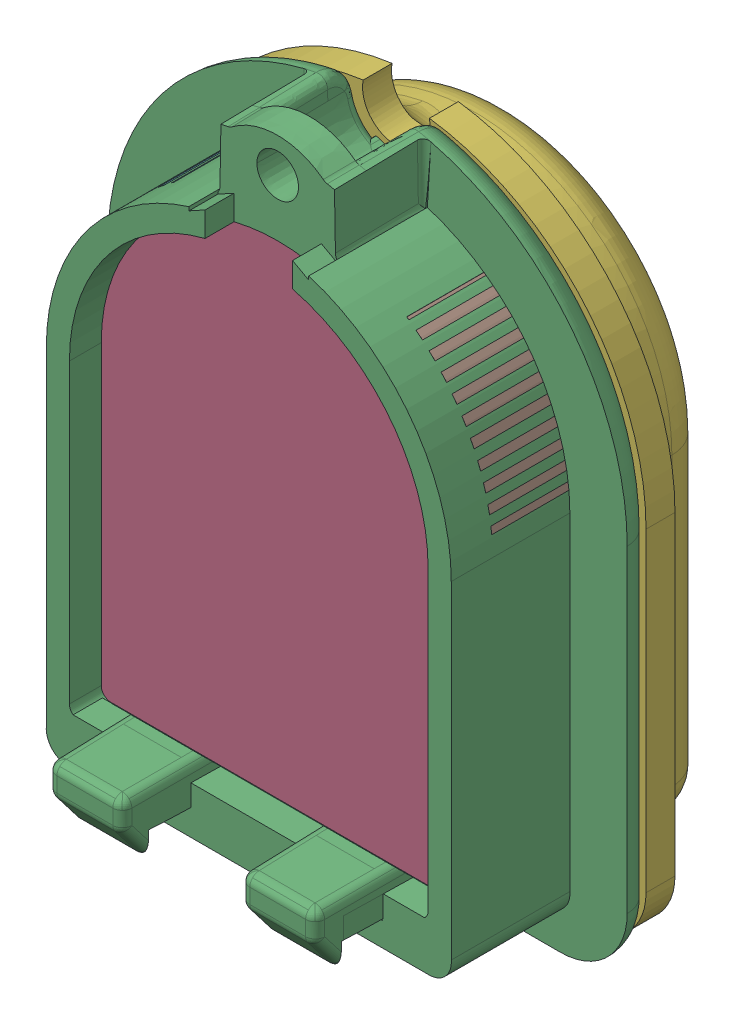
SolidWorks assembly newDesign, configuration 默认. Lengths in mm.
Overall size (26.95 34.26 17.16).
8 component instances, 7 part files, 21 mates.
Components (placement in the parent):
- NewBoardTip1-1: NewBoardTip1 [默认] at (-1.9035 7.7463 -5.5591) size (26.95 34.26 11.18)
- NewBoardlensnew-1: NewBoardlensnew [默认] at (-1.9035 7.7463 -5.5591) size (18.6 25.2 6)
- NewBoardSkin0.2-1: NewBoardSkin0.2 [默认] at (-1.9035 7.4963 -5.5591) x (-1 0 0) z (0 0 -1) size (23.9 30.06 5.2)
- NewSkin1-2: NewSkin1 [默认] at (-1.9035 7.4963 -5.5591) x (-1 0 0) z (0 0 -1) size (25.9 32.24 6)
- NewBoardsidelens1-1: NewBoardsidelens1 [默认] at (-1.9035 7.7463 -6.2091) size (6.4 7.71 4)
- NewBoardsidelens1-2: NewBoardsidelens1 [默认] at (-1.9035 7.7463 2.0909) x (-1 0 0) z (0 0 -1) size (6.4 7.71 4)
- NewBoardbottomlens-1: NewBoardbottomlens [默认] at (-5.9035 -10.5037 0.4409) x (1 0 0) z (0 1 0) size (8 4.5 2.35)
- NewBoardChessboardDigit-1: NewBoardChessboardDigit [默认] at (-15.1693 -0.6894 -10.3591) x (0 1 0) z (0 0 -1) size (22.5 14.3 0.4)
Mates (geometry in assembly coordinates):
- 同心1: concentric aligned: cylinder of BoardTip1-1 through (-1.9035 7.7463 51.2878) axis (0 0 -1) radius 9.3; cylinder of lensnew-1 through (-1.9035 7.7463 0.4409) axis (0 0 -1) radius 9.3
- 重合1: coincident anti-aligned: plane of BoardTip1-1 through (-1.9035 -8.1537 51.2878) normal (0 1 0); plane of lensnew-1 through (-11.2035 -8.1537 0.4409) normal (0 -1 0)
- 重合2: coincident aligned: plane of BoardTip1-1 through (-1.964 4.3089 -5.5591) normal (0 0 -1); plane of lensnew-1 through (-1.9035 7.7463 -5.5591) normal (0 0 -1)
- 重合3: coincident anti-aligned: plane of lensnew-1 through (-1.9035 7.7463 -5.5591) normal (0 0 -1); plane of Skin0.2-1 through (-1.9035 7.4963 -5.5591) normal (0 0 1)
- 同心2: concentric aligned: cone of BoardTip1-1 through (-1.9035 19.9963 -1.0591) axis (0 0 1); cylinder of Skin0.2-1 through (-1.9035 19.9963 -6.3091) axis (0 0 1) radius 2.75
- 宽度1: width aligned: plane of Skin0.2-1 through (-13.8535 7.4963 -5.5591) normal (-1 0 0); plane of BoardTip1-1 through (10.0465 7.4963 -5.5591) normal (1 0 0); plane of Skin0.2-1 through (-12.4035 7.7463 2.0909) normal (-1 0 0); plane of BoardTip1-1 through (8.5965 7.7463 2.0909) normal (1 0 0)
- 重合4: coincident anti-aligned: plane of Skin0.2-1 through (-1.9035 7.4963 -10.7591) normal (0 0 -1); plane of Skin1-2 through (-1.9035 7.4963 -10.7591) normal (0 0 1)
- 重合6: coincident anti-aligned: plane of BoardTip1-1 through (-16.7251 9.2061 -4.0591) normal (0.104528 0.994522 0); plane of sidelens1-1 through (8.4147 6.5638 -0.0591) normal (-0.104528 -0.994522 0)
- 重合7: coincident anti-aligned: plane of BoardTip1-1 through (-1.9035 7.7463 -4.0591) normal (0 0 1); plane of sidelens1-1 through (8.4147 6.5638 -4.0591) normal (0 0 -1)
- 同心3: concentric aligned: cylinder of BoardTip1-1 through (-1.9035 7.7463 2.0909) axis (0 0 -1) radius 10.5; cylinder of sidelens1-1 through (-1.9035 7.7463 -0.0591) axis (0 0 -1) radius 10.5
- 同心4: concentric anti-aligned: cylinder of BoardTip1-1 through (-1.9035 7.7463 2.0909) axis (0 0 -1) radius 10.5; cylinder of sidelens1-2 through (-1.9035 7.7463 -4.0591) axis (0 0 1) radius 10.5
- 重合8: coincident anti-aligned: plane of BoardTip1-1 through (12.0819 17.1622 -0.0591) normal (0.104528 -0.994522 0); plane of sidelens1-2 through (-13.0579 14.5199 -4.0591) normal (-0.104528 0.994522 0)
- 重合9: coincident anti-aligned: plane of BoardTip1-1 through (-1.9035 7.7463 -4.0591) normal (0 0 1); plane of sidelens1-2 through (-1.9035 7.7463 -4.0591) normal (0 0 -1)
- 重合10: coincident anti-aligned: plane of lensnew-1 through (-11.2035 -8.1537 0.4409) normal (0 -1 0); plane of bottomlens-1 through (-5.9035 -8.1537 0.4409) normal (0 1 0)
- 重合11: coincident anti-aligned: plane of BoardTip1-1 through (-5.9035 -18.1537 0.4409) normal (0 0 -1); plane of bottomlens-1 through (-5.9035 -8.1537 0.4409) normal (0 0 1)
- 重合12: coincident anti-aligned: plane of BoardTip1-1 through (2.0965 -18.1537 0.4409) normal (-1 0 0); plane of bottomlens-1 through (2.0965 -8.1537 0.4409) normal (1 0 0)
- 宽度4: width aligned: plane of BoardTip1-1 through (8.5965 7.7463 2.0909) normal (1 0 0); plane of BoardTip1-1 through (-12.4035 7.7463 2.0909) normal (-1 0 0); plane of ChessboardDigit-1 through (5.2465 4.9053 -10.7591) normal (1 0 0); plane of ChessboardDigit-1 through (-9.0535 9.0053 -10.7591) normal (-1 0 0)
- 距离2: distance = 2 mm aligned: plane of Skin1-2 through (7.3875 -9.3947 -5.5591) normal (0 -1 0); plane of ChessboardDigit-1 through (-2.9535 -7.3947 -10.7591) normal (0 -1 0)
- 重合14: coincident aligned: plane of Skin0.2-1 through (-1.9035 7.4963 -10.7591) normal (0 0 -1); plane of ChessboardDigit-1 through (-11.0693 7.5106 -10.7591) normal (0 0 -1)
- 宽度5: width aligned: plane of Skin1-2 through (-14.8535 7.4963 -5.5591) normal (-1 0 0); plane of Skin1-2 through (11.0465 7.4963 -5.5591) normal (1 0 0); plane of BoardSkin0.2-1 through (-13.8535 7.4963 -5.5591) normal (-1 0 0); plane of BoardSkin0.2-1 through (10.0465 7.4963 -5.5591) normal (1 0 0)
- 同心5: concentric aligned: cylinder of BoardSkin0.2-1 through (-1.9035 19.9963 -6.3091) axis (0 0 1) radius 2.75; cylinder of Skin1-2 through (-1.9035 19.9963 -6.3091) axis (0 0 1) radius 1.75
